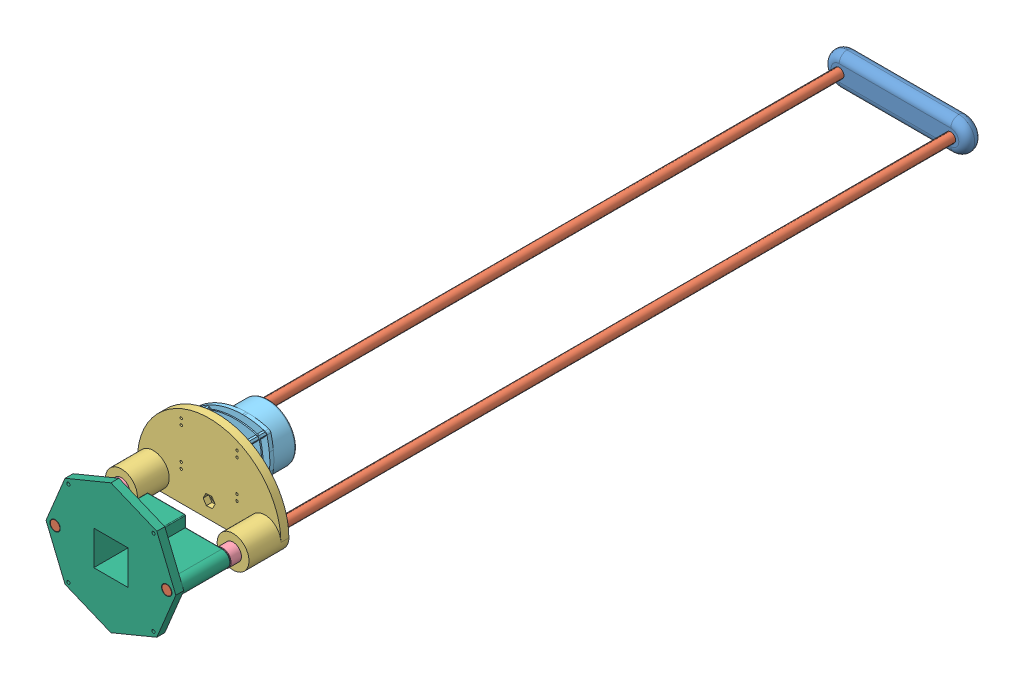
SolidWorks assembly ROCO318 all, configuration Default. Lengths in mm.
Overall size (180.03 171.4 1003).
10 component instances, 6 part files, 24 mates.
Components (placement in the parent):
- ROCO318 top extruded-1: ROCO318 top extruded [Default] at origin size (180 40 20)
- ROCO318 SMOOTH ROD-1: ROCO318 SMOOTH ROD [Default] at (-70 0 3) size (12 12 1000)
- ROCO318 SMOOTH ROD-2: ROCO318 SMOOTH ROD [Default] at (70 0 3) size (12 12 1000)
- ROCO318 extruded-1: ROCO318 extruded [Default] at (-86.0375 -1.7194 869.8666) x (1 -0.000253 0) z (0 0 1) size (180 110 50)
- BALL BEARING-2: BALL BEARING [Default] at (-70 0 872.8666) size (21 21 30)
- BALL BEARING-3: BALL BEARING [Default] at (-70 0 902.8666) x (0.94426 -0.3292 0) z (0 0 1) size (21 21 30)
- BALL BEARING-4: BALL BEARING [Default] at (70 0 872.8666) size (21 21 30)
- BALL BEARING-5: BALL BEARING [Default] at (70 0 902.8666) size (21 21 30)
- rplidar_main-2: rplidar_main [По умолчанию] at (-7.6108 45.4083 845.2666) x (-1 0 0) z (0 -1 0) size (98.5 57.7 70.02)
- ROCO318 bottom extruded 2-1: ROCO318 bottom extruded 2 [Default] at (0 0 1003) x (1 0 0) z (0 0 -1) size (162.78 162.78 70)
Mates (geometry in assembly coordinates):
- Coincident1: coincident: plane of ROCO318 top extruded-1 through (-70 0 3) normal (0 0 1); plane of ROCO318 SMOOTH ROD-1 through (-70 0 3) normal (0 0 -1)
- Coincident2: coincident: plane of ROCO318 top extruded-1 through (-70 0 3) normal (0 0 1); plane of ROCO318 SMOOTH ROD-1 through (-70 0 3) normal (0 0 -1)
- Coincident3: coincident: plane of ROCO318 top extruded-1 through (-70 0 3) normal (0 0 1); plane of ROCO318 SMOOTH ROD-1 through (-70 0 3) normal (0 0 -1)
- Concentric1: concentric: cylinder of ROCO318 top extruded-1 through (-70 0 20) axis (0 0 -1) radius 6; cylinder of ROCO318 SMOOTH ROD-1 through (-70 0 1003) axis (0 0 -1) radius 6
- Coincident4: coincident: circle of ROCO318 top extruded-1; cylinder of ROCO318 SMOOTH ROD-2 through (70 0 1003) axis (0 0 -1) radius 6
- Concentric2: concentric: cylinder of ROCO318 top extruded-1 through (70 0 20) axis (0 0 -1) radius 6; cylinder of ROCO318 SMOOTH ROD-2 through (70 0 1003) axis (0 0 -1) radius 6
- Coincident6: coincident: plane of ROCO318 top extruded-1 through (70 0 3) normal (0 0 1); plane of ROCO318 SMOOTH ROD-2 through (70 0 3) normal (0 0 -1)
- Coincident8: coincident: plane of ROCO318 extruded-1 through (-69.9999 -0.0001 871.6248) normal (0 0 1); plane of BALL BEARING-2 through (-69.9999 -0.0001 871.6248) normal (0 0 -1)
- Concentric4: concentric: cylinder of ROCO318 extruded-1 through (-69.9999 -0.0001 878.6248) axis (0 0 -1) radius 10.5; cylinder of BALL BEARING-2 through (-69.9999 -0.0001 901.6248) axis (0 0 -1) radius 10.5
- Coincident9: coincident: plane of BALL BEARING-2 through (-69.9999 -0.0001 901.6248) normal (0 0 1); plane of BALL BEARING-3 through (-70 0 901.6248) normal (0 0 -1)
- Concentric5: concentric: cylinder of ROCO318 extruded-1 through (-69.9999 -0.0001 878.6248) axis (0 0 -1) radius 10.5; cylinder of BALL BEARING-3 through (-70 0 931.6248) axis (0 0 -1) radius 10.5
- Coincident10: coincident: plane of ROCO318 extruded-1 through (70.0001 -0.0001 871.6248) normal (0 0 1); plane of BALL BEARING-4 through (70.0001 0 871.6248) normal (0 0 -1)
- Concentric6: concentric: cylinder of ROCO318 extruded-1 through (70.0001 -0.0001 878.6248) axis (0 0 -1) radius 10.5; cylinder of BALL BEARING-4 through (70.0001 0 901.6248) axis (0 0 -1) radius 10.5
- Coincident11: coincident: plane of BALL BEARING-4 through (70.0001 0 901.6248) normal (0 0 1); plane of BALL BEARING-5 through (70 -0.0001 901.6248) normal (0 0 -1)
- Concentric7: concentric: cylinder of ROCO318 extruded-1 through (70.0001 -0.0001 878.6248) axis (0 0 -1) radius 10.5; cylinder of BALL BEARING-5 through (70 -0.0001 931.6248) axis (0 0 -1) radius 10.5
- Coincident14: coincident: circle of ROCO318 extruded-1; plane of rplidar_main-2 through (-7.0976 45.4083 868.6248) normal (0 0 1)
- Coincident15: coincident: cylinder of ROCO318 SMOOTH ROD-2 through (70 0 1003) axis (0 0 -1) radius 6; circle of BALL BEARING-5
- Coincident16: coincident: cylinder of ROCO318 SMOOTH ROD-2 through (70 0 1003) axis (0 0 -1) radius 6; circle of BALL BEARING-4
- Coincident17: coincident: cylinder of ROCO318 SMOOTH ROD-2 through (70 0 1003) axis (0 0 -1) radius 6; circle of BALL BEARING-5
- Coincident19: coincident: plane of ROCO318 SMOOTH ROD-1 through (-70 0 1003) normal (0 0 1); circle of ROCO318 bottom extruded 2-1
- Coincident20: coincident: plane of ROCO318 SMOOTH ROD-2 through (70 0 1003) normal (0 0 1); circle of ROCO318 bottom extruded 2-1
- Concentric11: concentric: cylinder of ROCO318 SMOOTH ROD-2 through (70 0 1003) axis (0 0 -1) radius 6; cylinder of ROCO318 bottom extruded 2-1 through (70 0 1003) axis (0 0 -1) radius 6.5
- Concentric12: concentric: cylinder of ROCO318 SMOOTH ROD-1 through (-70 0 1003) axis (0 0 -1) radius 6; cylinder of ROCO318 bottom extruded 2-1 through (-70 0 1003) axis (0 0 -1) radius 6.5
- Concentric13: concentric: cylinder of ROCO318 SMOOTH ROD-1 through (-70 0 1003) axis (0 0 -1) radius 6; cylinder of BALL BEARING-3 through (-70 0 931.6248) axis (0 0 -1) radius 10.5
